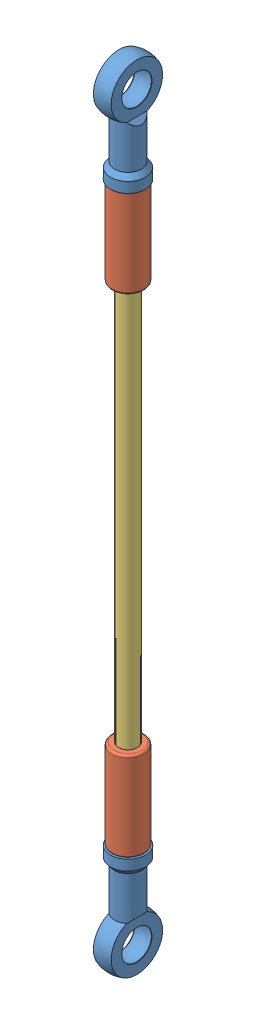
SolidWorks assembly AntebrazoCompleto, configuration Predeterminado. Lengths in mm.
Overall size (16.61 295.2 20.2).
5 component instances, 3 part files, 11 mates.
Components (placement in the parent):
- uniball-Cuerpo-1: uniball-Cuerpo [Predeterminado] at (-16.0893 11.759 40.6494) size (13 40.6 20.2)
- uniball-Cuerpo-2: uniball-Cuerpo [Predeterminado] at (-16.0893 -263.241 40.6494) x (-1 0 0) z (0 0 1) size (13 40.6 20.2)
- Acople-Antebrazo-RUniball-1: Acople-Antebrazo-RUniball [Predeterminado] at (-16.0893 -199.741 40.6494) x (-0.837169 0 -0.546944) z (0 -1 0) size (12 12 53)
- Acople-Antebrazo-RUniball-2: Acople-Antebrazo-RUniball [Predeterminado] at (-16.0893 -51.741 40.6494) x (-0.837169 0 -0.546944) z (0 1 0) size (12 12 53)
- Antebrazo-1: Antebrazo [Predeterminado] at (-16.0893 -227.741 40.6494) x (-0.837169 0 -0.546944) z (0 1 0) size (7 7 204)
Mates (geometry in assembly coordinates):
- Paralelo1: parallel anti-aligned: plane of uniball-Cuerpo-2 through (-9.5893 -232.741 40.6494) normal (0 1 0); plane of uniball-Cuerpo-1 through (-22.5893 -18.741 40.6494) normal (0 -1 0)
- Coincidente2: coincident anti-aligned: plane of uniball-Cuerpo-2 through (-9.5893 -232.741 40.6494) normal (0 1 0); plane of Acople-Antebrazo-RUniball-1 through (-16.0893 -232.741 40.6494) normal (0 -1 0)
- Concéntrica2: concentric anti-aligned: circle of Acople-Antebrazo-RUniball-2; circle of Acople-Antebrazo-RUniball-1
- Coincidente3: coincident anti-aligned: plane of uniball-Cuerpo-1 through (-22.5893 -18.741 40.6494) normal (0 -1 0); plane of Acople-Antebrazo-RUniball-2 through (-16.0893 -18.741 40.6494) normal (0 1 0)
- Coincidente4: coincident anti-aligned: plane of Acople-Antebrazo-RUniball-2 through (-16.0893 -23.741 40.6494) normal (0 -1 0); plane of Antebrazo-1 through (-16.0893 -23.741 40.6494) normal (0 1 0)
- Coincidente5: coincident anti-aligned: plane of Acople-Antebrazo-RUniball-1 through (-16.0893 -227.741 40.6494) normal (0 1 0); plane of Antebrazo-1 through (-16.0893 -227.741 40.6494) normal (0 -1 0)
- Concéntrica4: concentric aligned: circle of Acople-Antebrazo-RUniball-2; circle of Antebrazo-1
- Concéntrica5: concentric anti-aligned: circle of Acople-Antebrazo-RUniball-1; circle of Antebrazo-1
- Concéntrica6: concentric aligned: circle of Acople-Antebrazo-RUniball-2; cylinder of Antebrazo-1 through (-16.0893 -23.741 40.6494) axis (0 -1 0) radius 3.5
- Concéntrica7: concentric aligned: cylinder of uniball-Cuerpo-1 through (-16.0893 3.259 40.6494) axis (0 -1 0) radius 3; circle of Acople-Antebrazo-RUniball-2
- Concéntrica8: concentric aligned: cylinder of uniball-Cuerpo-2 through (-16.0893 -254.741 40.6494) axis (0 1 0) radius 3; cylinder of Acople-Antebrazo-RUniball-1 through (-16.0893 -252.741 40.6494) axis (0 1 0) radius 2.75
